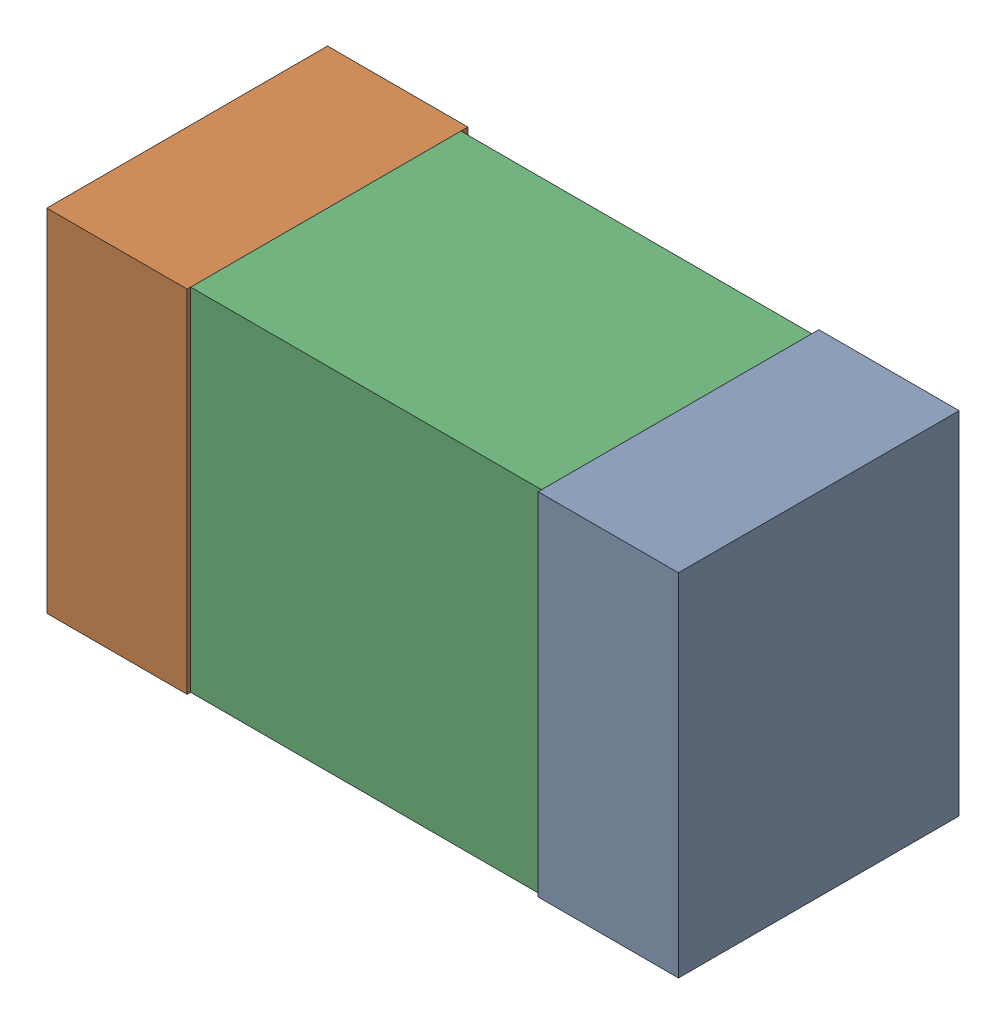
SolidWorks assembly L300_1PCB, configuration Default. Lengths in mm.
Overall size (1.8 1 0.8).
6 component instances, 2 part files, 0 mates.
Components (placement in the parent):
- 854785840-1: 854785840 [Default] at (134.5934 121.4591 -2.4638) size (0.4 1 0.8)
  - Extruded_4-1: Extruded_4 [Default] at origin size (0.4 1 0.8)
- 854785840-2: 854785840 [Default] at (133.1934 121.4591 -2.4638) size (0.4 1 0.8)
  - Extruded_4-1: Extruded_4 [Default] at origin size (0.4 1 0.8)
- 846483152-1: 846483152 [Default] at (133.8934 121.4591 -2.4438) size (1 1 0.77)
  - Extruded_3-1: Extruded_3 [Default] at origin size (1 1 0.77)
